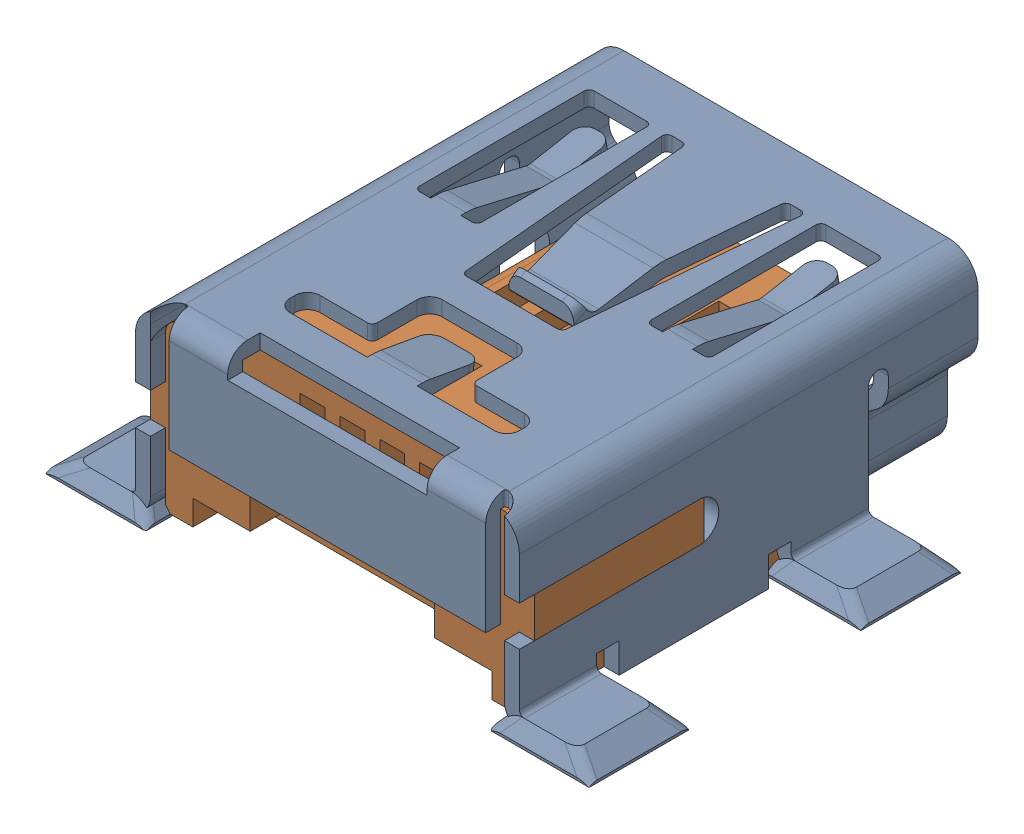
SolidWorks assembly Li-MINIUSB - MEASURED, configuration Default. Lengths in mm.
Overall size (10.9 4.8 9.4).
3 component instances, 3 part files, 6 mates.
Components (placement in the parent):
- Li-MINIUSBSHELL-1: Li-MINIUSBSHELL [Default] at origin size (10.9 3.75 9.4)
- Li-MINIUSBCORE-1: Li-MINIUSBCORE [Default] at (0 0 6.7) x (-1 0 0) z (0 0 -1) size (7.7 4.5 8.2)
- MINI USB SOLDER-1: MINI USB SOLDER [Default] at (0 -0.05 -0.4) x (-1 0 0) z (0 0 -1) (suppressed, hidden)
Mates (geometry in assembly coordinates):
- Coincident1: coincident anti-aligned: plane of MINIUSBCORE-1 through (0 0 6.7) normal (-1 0 0); plane of assembly through (0 0 0) normal (1 0 0)
- Coincident2: coincident aligned: plane of MINIUSBSHELL-1 through (3.175 3.4 6.7) normal (0 0 -1); plane of MINIUSBCORE-1 through (0 0 6.7) normal (0 0 -1)
- Coincident4: coincident aligned: plane of MINIUSBSHELL-1 through (0 0 0) normal (0 1 0); plane of MINIUSBCORE-1 through (0 0 6.7) normal (0 1 0)
- Coincident9: coincident: plane of assembly; plane of MINI USB SOLDER-1 through (0 -0.05 -0.4) normal (0 0 -1); plane of Li-MINIUSBSHELL-1 through (-3.85 0 -0.4) normal (0 0 1)
- Coincident11: coincident: plane of MINI USB SOLDER-1 through (0 -0.05 -0.4) normal (-1 0 0); plane of assembly through (0 0 0) normal (1 0 0)
- Coincident12: coincident anti-aligned: plane of Li-MINIUSBSHELL-1 through (0 -0.05 0) normal (0 -1 0); unknown of MINI USB SOLDER-1
